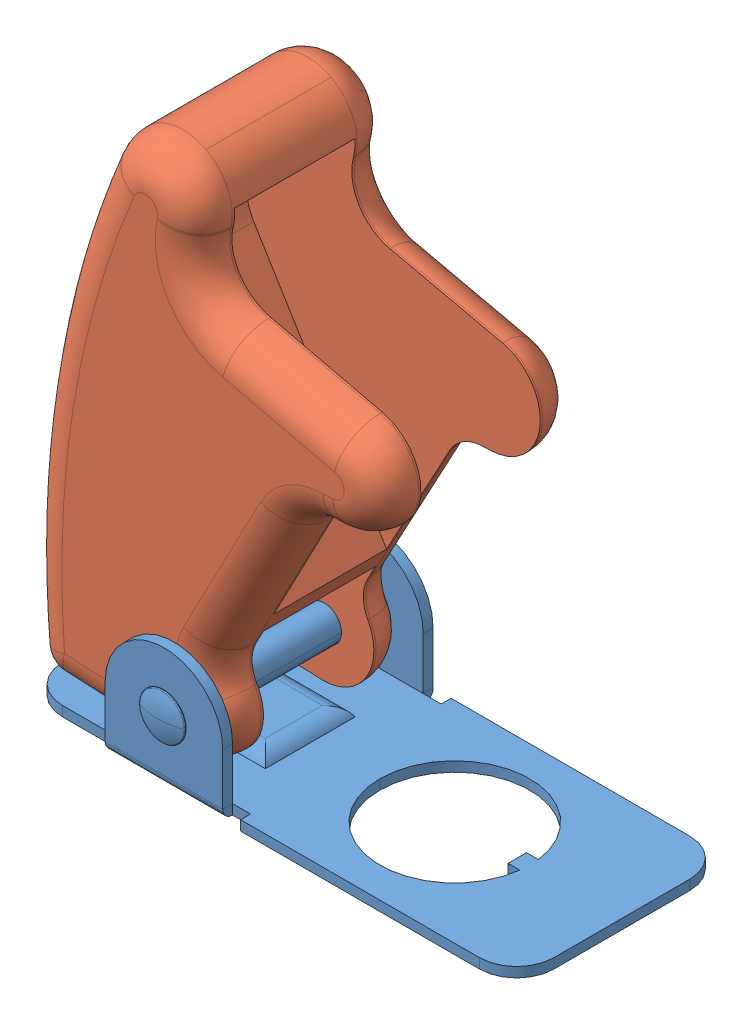
SolidWorks assembly Schalter-Schutz, configuration Standard. Lengths in mm.
Overall size (41.37 44.17 17.6).
3 component instances, 2 part files, 1 mates.
Components (placement in the parent):
- r171000aaa_open^Schalter-Schutz-1: r171000aaa_open^Schalter-Schutz [Standard] at origin size (41.37 44.17 17.6) (virtual, flexible)
  - r171000aaa_open1^r171000aaa_open_Schalter-Schutz-1: r171000aaa_open1^r171000aaa_open_Schalter-Schutz [Standard] at origin size (40.5 9.75 17.6) (virtual)
  - r171000aaa_open2^r171000aaa_open_Schalter-Schutz-1: r171000aaa_open2^r171000aaa_open_Schalter-Schutz [Standard] at (-0.3684 -0.9931 0) x (0.997756 -0.066955 0) z (0 0 1) size (28.21 42.38 16.19) (virtual)
Mates (geometry in assembly coordinates):
- Coincident1: coordinate: point of r171000aaa_open^Schalter-Schutz-1
